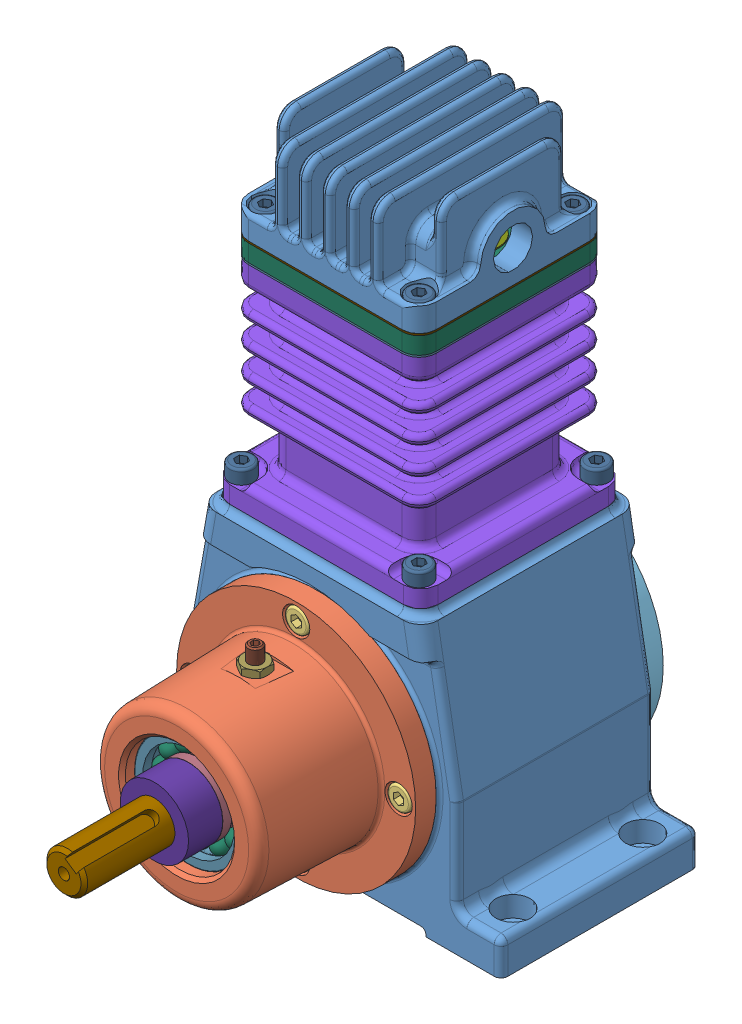
SolidWorks assembly Assemblage1, configuration Défaut. Lengths in mm.
Overall size (106 177 144.5).
85 component instances, 35 part files, 6 mates.
Components (placement in the parent):
- se_fixe-1: se_fixe [Défaut] at (-86.9567 -100.0991 13.75) size (106 177 111.5)
  - corps-1: corps [Défaut] at origin size (106 82 64)
  - Palier-1: Palier [Défaut] at (53 38 42) x (0 0 -1) z (1 0 0) size (50 70 70)
  - Vis Chc M4-8-1: Vis Chc M4-8 [Défaut] at (53 68 3) x (-1 0 0) z (0 0 -1) size (7 7 12)
  - Vis Chc M4-8-2: Vis Chc M4-8 [Défaut] at (83 38 3) x (-0.5 -0.866025 0) z (0 0 -1) size (7 7 12)
  - Vis Chc M4-8-3: Vis Chc M4-8 [Défaut] at (53 8 3) x (-0.5 -0.866025 0) z (0 0 -1) size (7 7 12)
  - Vis Chc M4-8-4: Vis Chc M4-8 [Défaut] at (23 38 3) x (-0.5 -0.866025 0) z (0 0 -1) size (7 7 12)
  - joint plat_couvercle-1: joint plat_couvercle [Défaut] at (53 38 -59.5) size (70 70 0.5)
  - couvercle-1: couvercle [Défaut] at (53 38 -59.5) x (-1 0 0) z (0 0 -1) size (70 70 6)
  - Bouchon-1: Bouchon [Défaut] at (53 25 -65.5) size (13 15.01 12)
  - Joint circulaire A-1: Joint circulaire A [Défaut] at (53 25 -63.5) size (15 15 2)
  - Vis Chc M4-8-5: Vis Chc M4-8 [Défaut] at (53 68 -61.5) size (7 7 12)
  - Vis Chc M4-8-6: Vis Chc M4-8 [Défaut] at (23 38 -61.5) size (7 7 12)
  - Vis Chc M4-8-7: Vis Chc M4-8 [Défaut] at (53 8 -61.5) size (7 7 12)
  - Vis Chc M4-8-8: Vis Chc M4-8 [Défaut] at (83 38 -61.5) size (7 7 12)
  - cylindre-1: cylindre [Défaut] at (53 82 -29) size (61 64 60)
  - chemise-1: chemise [Défaut] at (53 143 -29) x (-0.620898 0 0.783891) z (0 -1 0) size (38 38 60)
  - Vis Chc M4-14-1: Vis Chc M4-14 [Défaut] at (27 87 -3) x (1 0 0) z (0 -1 0) size (7 7 18)
  - Vis Chc M4-14-2: Vis Chc M4-14 [Défaut] at (79 87 -3) x (1 0 0) z (0 -1 0) size (7 7 18)
  - Vis Chc M4-14-3: Vis Chc M4-14 [Défaut] at (79 87 -55) x (1 0 0) z (0 -1 0) size (7 7 18)
  - Vis Chc M4-14-4: Vis Chc M4-14 [Défaut] at (27 87 -55) x (1 0 0) z (0 -1 0) size (7 7 18)
  - Vis sans tête HC à téton long38-1: Vis sans tête HC à téton long38 [Défaut] at (53 68.5 19) x (-1 0 0) z (0 0 -1) size (4 16 4)
  - Ecrou HM, M4SLDPRT-1: Ecrou HM, M4SLDPRT [Défaut] at (53 62 19) x (-1 0 0) z (0 -1 0) size (7 8.08 2.2)
  - entretoise_be-1: entretoise_be [Défaut] at (53 38 4) size (32 32 25.5)
  - joint plat_cylindre-1: joint plat_cylindre [Défaut] at (53 143 -29) x (0 0 -1) z (0 1 0) size (55 55 0.5)
  - porte clapets-1: porte clapets [Défaut] at (53 148.5 -29) x (0 0 1) z (1 0 0) size (55 5 55)
  - clapet-1: clapet [Défaut] at (62 148.85 -37) x (0 0 -1) z (0 -1 0) size (29 13 0.35)
  - clapet-2: clapet [Défaut] at (44 143.15 -29.5) x (0 0 1) z (0 1 0) size (29 13 0.35)
  - Vis Chc M2-5-1: Vis Chc M2-5 [Défaut] at (65 148.85 -17) x (-0.5 0 -0.866025) z (0 -1 0) size (3.8 3.8 7)
  - Vis Chc M2-5-2: Vis Chc M2-5 [Défaut] at (59 148.85 -17) x (-0.5 0 -0.866025) z (0 -1 0) size (3.8 3.8 7)
  - Vis Chc M2-5-3: Vis Chc M2-5 [Défaut] at (47 143.15 -49.5) x (0.5 0 -0.866025) z (0 1 0) size (3.8 3.8 7)
  - Vis Chc M2-5-4: Vis Chc M2-5 [Défaut] at (41 143.15 -49.5) x (0.5 0 -0.866025) z (0 1 0) size (3.8 3.8 7)
  - joint plat_culasse-1: joint plat_culasse [Défaut] at (53 149 -29) x (1 0 0) z (0 -1 0) size (55 55 0.5)
  - culasse-1: culasse [Défaut] at (53 149 -29) x (0 0 1) z (-1 0 0) size (55 28 55)
  - Vis Chc M4-14-5: Vis Chc M4-14 [Défaut] at (30.5 152 -6.5) x (-0.5 0 -0.866025) z (0 -1 0) size (7 7 18)
  - Vis Chc M4-14-6: Vis Chc M4-14 [Défaut] at (30.5 152 -51.5) x (0.5 0 0.866025) z (0 -1 0) size (7 7 18)
  - Vis Chc M4-14-7: Vis Chc M4-14 [Défaut] at (75.5 152 -6.5) x (-0.5 0 -0.866025) z (0 -1 0) size (7 7 18)
  - Vis Chc M4-14-8: Vis Chc M4-14 [Défaut] at (75.5 152 -51.5) x (-0.5 0 0.866025) z (0 -1 0) size (7 7 18)
- se_bielle-1: se_bielle [Défaut] at (-41.3104 -72.8193 -15.25) x (0.994467 -0.105053 0) z (0 0 1) size (23.14 89 16)
  - bielle-1: bielle [Défaut] at origin size (23.14 89 16)
  - Coussinet_cylindrique, 12x16x16-1: Coussinet_cylindrique, 12x16x16 [Défaut] at (0 0 -8) x (0 0 1) z (-1 0 0) size (16 16 16)
  - Coussinet_cylindrique, 9x12x14-1: Coussinet_cylindrique, 9x12x14 [Défaut] at (0 70 -7) x (0 0 1) z (-1 0 0) size (14 12 12)
- se_piston-1: se_piston [Défaut] at (-33.9567 -3.2066 -15.25) x (0 0 1) z (-1 0 0) size (35 32.5 35)
  - piston-1: piston [Défaut] at origin size (35 32.5 35)
  - segment racleur-1: segment racleur [Défaut] at (0 17 0) size (35 2 35)
  - segment-1: segment [Défaut] at (0 14.5 0) size (35 1.5 35)
  - segment-2: segment [Défaut] at (0 12 0) size (35 1.5 35)
  - axe du piston-1: axe du piston [Défaut] at (-16.5 0 0) x (0 0 -1) z (1 0 0) size (9 9 33)
- se_vilebrequin-1: se_vilebrequin [Défaut] at (-33.9567 -62.0991 88.75) x (0 0 -1) z (0.82463 -0.565672 0) size (116 48 46.61)
  - Vilebrequin-1: Vilebrequin [Défaut] at origin size (97.5 48 46.61)
  - Maneton-1: Maneton [Défaut] at (116 -13 0) x (0 0.924225 0.381849) z (-1 0 0) size (12 12 32.5)
  - anneau elastique pour arbre, 12x1-1: anneau elastique pour arbre, 12x1 [Défaut] at (114.1 -13 0) x (0 0 1) z (-1 0 0) size (14.25 16.29 1)
  - rondelle-1: rondelle [Défaut] at (112 -13 0) x (0 0 -1) z (1 0 0) size (20 20 1.1)
  - Roulement 6002-1: Roulement 6002 [Défaut] at (71 0 0) size (9 32 32)
    - Roulement_r1rb_Bint33-1: Roulement_r1rb_Bint33 [Défaut] at origin size (9 20.1 20.1)
    - Roulement_r1rb_Bext33-1: Roulement_r1rb_Bext33 [Défaut] at origin size (9 32 32)
    - Roulement_r1rb_Eroul33-1: Roulement_r1rb_Eroul33 [Défaut] at (0.3 0 -7.8) size (5.1 5.1 5.1)
    - Roulement_r1rb_Eroul33-2: Roulement_r1rb_Eroul33 [Défaut] at (0.3 3.9 -6.755) x (1 0 0) z (0 -0.5 0.866025) size (5.1 5.1 5.1)
    - Roulement_r1rb_Eroul33-3: Roulement_r1rb_Eroul33 [Défaut] at (0.3 6.755 -3.9) x (1 0 0) z (0 -0.866025 0.5) size (5.1 5.1 5.1)
    - Roulement_r1rb_Eroul33-4: Roulement_r1rb_Eroul33 [Défaut] at (0.3 7.8 0) x (1 0 0) z (0 -1 0) size (5.1 5.1 5.1)
    - Roulement_r1rb_Eroul33-5: Roulement_r1rb_Eroul33 [Défaut] at (0.3 6.755 3.9) x (1 0 0) z (0 -0.866025 -0.5) size (5.1 5.1 5.1)
    - Roulement_r1rb_Eroul33-6: Roulement_r1rb_Eroul33 [Défaut] at (0.3 3.9 6.755) x (1 0 0) z (0 -0.5 -0.866025) size (5.1 5.1 5.1)
    - Roulement_r1rb_Eroul33-7: Roulement_r1rb_Eroul33 [Défaut] at (0.3 0 7.8) x (1 0 0) z (0 0 -1) size (5.1 5.1 5.1)
    - Roulement_r1rb_Eroul33-8: Roulement_r1rb_Eroul33 [Défaut] at (0.3 -3.9 6.755) x (1 0 0) z (0 0.5 -0.866025) size (5.1 5.1 5.1)
    - Roulement_r1rb_Eroul33-9: Roulement_r1rb_Eroul33 [Défaut] at (0.3 -6.755 3.9) x (1 0 0) z (0 0.866025 -0.5) size (5.1 5.1 5.1)
    - Roulement_r1rb_Eroul33-10: Roulement_r1rb_Eroul33 [Défaut] at (0.3 -7.8 0) x (1 0 0) z (0 1 0) size (5.1 5.1 5.1)
    - Roulement_r1rb_Eroul33-11: Roulement_r1rb_Eroul33 [Défaut] at (0.3 -6.755 -3.9) x (1 0 0) z (0 0.866025 0.5) size (5.1 5.1 5.1)
    - Roulement_r1rb_Eroul33-12: Roulement_r1rb_Eroul33 [Défaut] at (0.3 -3.9 -6.755) x (1 0 0) z (0 0.5 0.866025) size (5.1 5.1 5.1)
  - Roulement 6002-2: Roulement 6002 [Défaut] at (36.5 0 0) size (9 32 32)
    - Roulement_r1rb_Bint33-1: Roulement_r1rb_Bint33 [Défaut] at origin size (9 20.1 20.1)
    - Roulement_r1rb_Bext33-1: Roulement_r1rb_Bext33 [Défaut] at origin size (9 32 32)
    - Roulement_r1rb_Eroul33-1: Roulement_r1rb_Eroul33 [Défaut] at (0.3 0 -7.8) size (5.1 5.1 5.1)
    - Roulement_r1rb_Eroul33-2: Roulement_r1rb_Eroul33 [Défaut] at (0.3 3.9 -6.755) x (1 0 0) z (0 -0.5 0.866025) size (5.1 5.1 5.1)
    - Roulement_r1rb_Eroul33-3: Roulement_r1rb_Eroul33 [Défaut] at (0.3 6.755 -3.9) x (1 0 0) z (0 -0.866025 0.5) size (5.1 5.1 5.1)
    - Roulement_r1rb_Eroul33-4: Roulement_r1rb_Eroul33 [Défaut] at (0.3 7.8 0) x (1 0 0) z (0 -1 0) size (5.1 5.1 5.1)
    - Roulement_r1rb_Eroul33-5: Roulement_r1rb_Eroul33 [Défaut] at (0.3 6.755 3.9) x (1 0 0) z (0 -0.866025 -0.5) size (5.1 5.1 5.1)
    - Roulement_r1rb_Eroul33-6: Roulement_r1rb_Eroul33 [Défaut] at (0.3 3.9 6.755) x (1 0 0) z (0 -0.5 -0.866025) size (5.1 5.1 5.1)
    - Roulement_r1rb_Eroul33-7: Roulement_r1rb_Eroul33 [Défaut] at (0.3 0 7.8) x (1 0 0) z (0 0 -1) size (5.1 5.1 5.1)
    - Roulement_r1rb_Eroul33-8: Roulement_r1rb_Eroul33 [Défaut] at (0.3 -3.9 6.755) x (1 0 0) z (0 0.5 -0.866025) size (5.1 5.1 5.1)
    - Roulement_r1rb_Eroul33-9: Roulement_r1rb_Eroul33 [Défaut] at (0.3 -6.755 3.9) x (1 0 0) z (0 0.866025 -0.5) size (5.1 5.1 5.1)
    - Roulement_r1rb_Eroul33-10: Roulement_r1rb_Eroul33 [Défaut] at (0.3 -7.8 0) x (1 0 0) z (0 1 0) size (5.1 5.1 5.1)
    - Roulement_r1rb_Eroul33-11: Roulement_r1rb_Eroul33 [Défaut] at (0.3 -6.755 -3.9) x (1 0 0) z (0 0.866025 0.5) size (5.1 5.1 5.1)
    - Roulement_r1rb_Eroul33-12: Roulement_r1rb_Eroul33 [Défaut] at (0.3 -3.9 -6.755) x (1 0 0) z (0 0.5 0.866025) size (5.1 5.1 5.1)
  - entretoise_bi-1: entretoise_bi [Défaut] at (71 0 0) x (0 0 1) z (-1 0 0) size (20 20 25.5)
  - entretoise-1: entretoise [Défaut] at (36.5 0 0) x (0 0 1) z (-1 0 0) size (20 20 10)
Mates (geometry in assembly coordinates):
- Coaxiale1: concentric aligned: cylinder of se_fixe-1/chemise-1 through (-33.9567 -17.0991 -15.25) axis (0 1 0) radius 17.5; cylinder of se_piston-1/piston-1 through (-33.9567 38.1742 -15.25) axis (0 1 0) radius 17.5
- Coaxiale3: concentric aligned: cylinder of se_bielle-1/Coussinet_cylindrique, 9x12x14-1 through (-33.9567 -3.2066 -22.25) axis (0 0 -1) radius 4.5; cylinder of se_piston-1/axe du piston-1 through (-33.9567 -3.2066 1.25) axis (0 0 -1) radius 4.5
- Coaxiale4: concentric aligned: cylinder of se_fixe-1/Palier-1 through (-33.9567 -62.0991 68.0584) axis (0 0 1) radius 16; cylinder of se_vilebrequin-1/Roulement 6002-2/Roulement_r1rb_Bext33-1 through (-33.9567 -62.0991 52.25) axis (0 0 1) radius 16
- Coaxiale5: concentric aligned: cylinder of se_bielle-1/Coussinet_cylindrique, 12x16x16-1 through (-41.3104 -72.8193 -23.25) axis (0 0 -1) radius 6; cylinder of se_vilebrequin-1/Maneton-1 through (-41.3104 -72.8193 -7.25) axis (0 0 -1) radius 6
- Coïncidente4: coincident anti-aligned: plane of se_bielle-1/bielle-1 through (-41.3104 -72.8193 -23.25) normal (0 0 -1); plane of se_vilebrequin-1/rondelle-1 through (-41.3104 -72.8193 -23.25) normal (0 0 1)
- Coïncidente6: coincident anti-aligned: plane of se_fixe-1/entretoise_be-1 through (-33.9567 -62.0991 43.25) normal (0 0 1); plane of se_vilebrequin-1/Roulement 6002-2/Roulement_r1rb_Bext33-1 through (-46.9034 -53.218 43.25) normal (0 0 -1)
